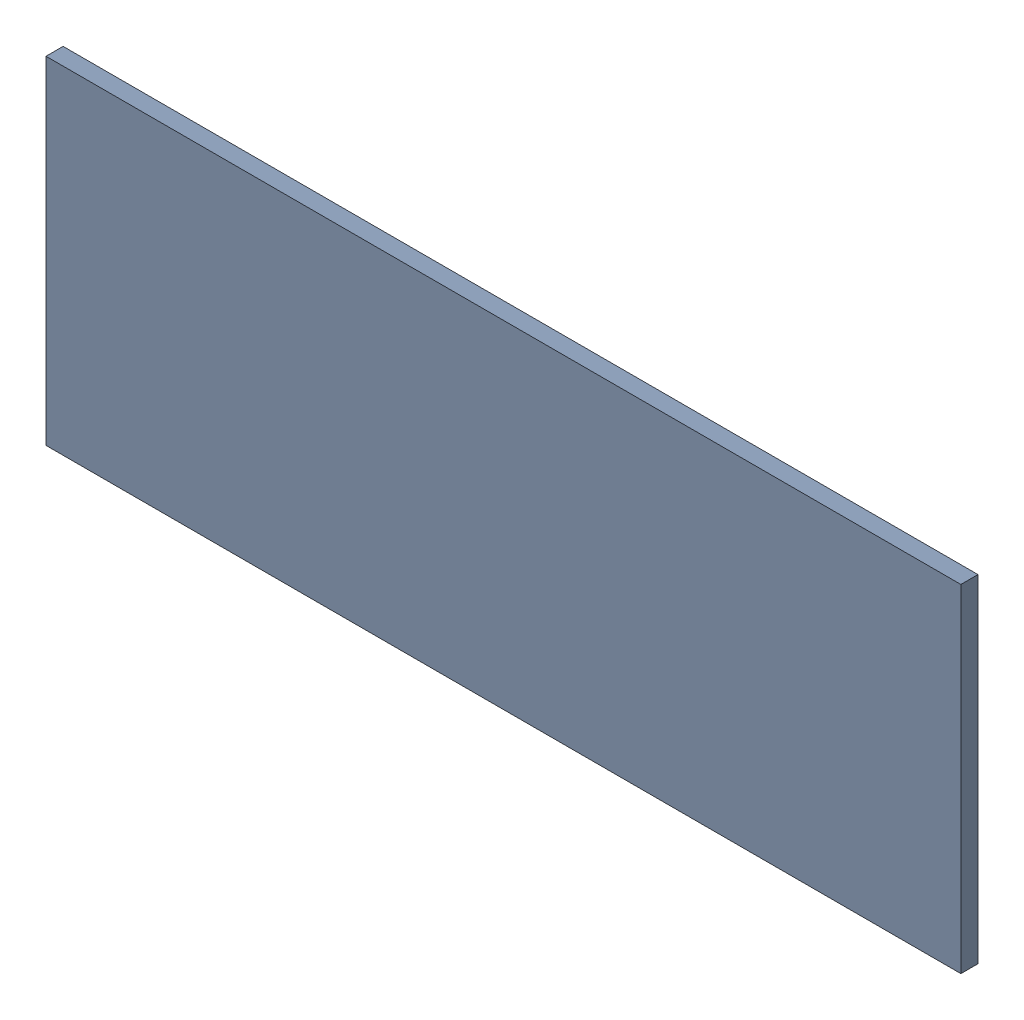
SolidWorks assembly Pad RAK4600-27(29.2mm,18.75mm) on Top Layer, configuration Predeterminado. Lengths in mm.
Overall size (1.9 0.7 0.04).
2 component instances, 1 part files, 0 mates.
Components (placement in the parent):
- Pad RAK4600-27(29.2mm,18.75mm) on Top Layer-1-1: Pad RAK4600-27(29.2mm,18.75mm) on Top Layer-1 [Predeterminado] at (-68.317 -44.187 -0.0457) size (1.9 0.7 0.04)
  - Pad RAK4600-27(29.2mm,18.75mm) on Top Layer-Part-1-1: Pad RAK4600-27(29.2mm,18.75mm) on Top Layer-Part-1 [Predeterminado] at origin size (1.9 0.7 0.04)
